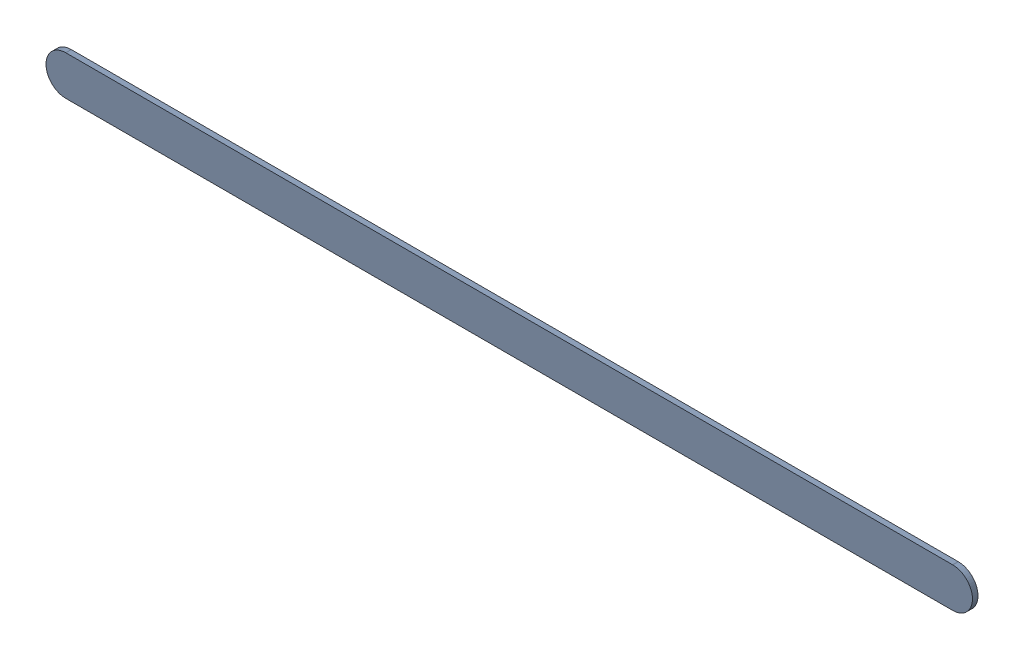
SolidWorks assembly Track (24.4mm,53.5mm)(30.1mm,53.5mm) on Top Layer, configuration Predeterminado. Lengths in mm.
Overall size (5.95 0.25 0.04).
2 component instances, 1 part files, 0 mates.
Components (placement in the parent):
- Track (24.4mm,53.5mm)(30.1mm,53.5mm) on Top Layer-1-1: Track (24.4mm,53.5mm)(30.1mm,53.5mm) on Top Layer-1 [Predeterminado] at (-68.317 -44.187 -0.0457) size (5.95 0.25 0.04)
  - Track (24.4mm,53.5mm)(30.1mm,53.5mm) on Top Layer-Part-1-1: Track (24.4mm,53.5mm)(30.1mm,53.5mm) on Top Layer-Part-1 [Predeterminado] at origin size (5.95 0.25 0.04)
